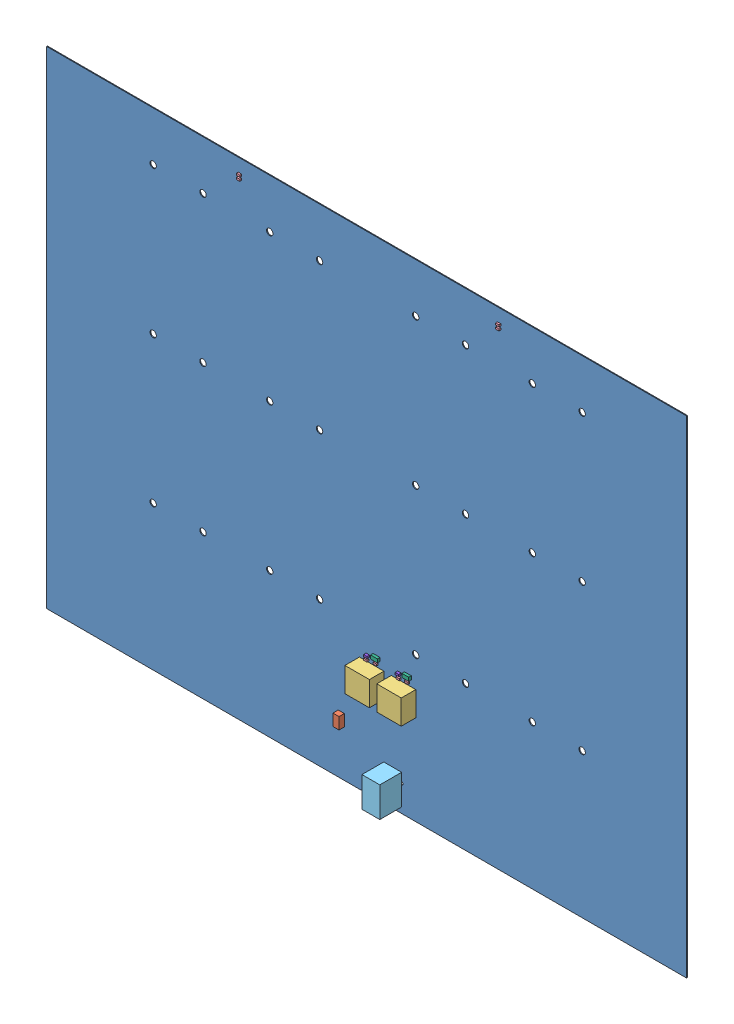
SolidWorks assembly ToasterChargerPcb_November25, configuration Default. Lengths in mm.
Overall size (318.77 242.57 11.41).
55 component instances, 8 part files, 0 mates.
Components (placement in the parent):
- Board-1: Board [Default] at (0 0 -0.4115) size (318.77 242.57 0.41)
- C7_47uF-1: C7_47uF [Default] at origin size (3.05 5.79 2.67)
  - 743509024-1: 743509024 [Default] at (197.7136 76.9366 0.127) size (3.05 5.79 2.67)
    - Extruded-1: Extruded [Default] at origin size (3.05 5.79 2.67)
- U2-1: U2 [Default] at origin size (12.19 12.19 7.24)
  - 580494096-1: 580494096 [Default] at (228.599 101.728 0) size (12.19 12.19 7.24)
    - Extruded_2-1: Extruded_2 [Default] at origin size (12.19 12.19 7.24)
- U1-1: U1 [Default] at origin size (12.19 12.19 7.24)
  - 580494096-1: 580494096 [Default] at (212.724 101.728 0) size (12.19 12.19 7.24)
    - Extruded_2-1: Extruded_2 [Default] at origin size (12.19 12.19 7.24)
- R6-1: R6 [Default] at origin size (1.7 0.95 0.9)
  - 580483600-1: 580483600 [Default] at (230.759 109.347 0) size (1.7 0.95 0.9)
    - Extruded_3-1: Extruded_3 [Default] at origin size (1.7 0.95 0.9)
- R5-1: R5 [Default] at origin size (1.7 0.95 0.9)
  - 580483600-1: 580483600 [Default] at (226.568 108.839 0) size (1.7 0.95 0.9)
    - Extruded_3-1: Extruded_3 [Default] at origin size (1.7 0.95 0.9)
- R3-1: R3 [Default] at origin size (1.7 0.95 0.9)
  - 580483600-1: 580483600 [Default] at (215.138 109.474 0) size (1.7 0.95 0.9)
    - Extruded_3-1: Extruded_3 [Default] at origin size (1.7 0.95 0.9)
- R1-1: R1 [Default] at origin size (1.7 0.95 0.9)
  - 580483600-1: 580483600 [Default] at (210.439 108.839 0) size (1.7 0.95 0.9)
    - Extruded_3-1: Extruded_3 [Default] at origin size (1.7 0.95 0.9)
- P1-1: P1 [Default] at origin size (8.89 14.99 10.87)
  - 743508640-1: 743508640 [Default] at (223.3168 61.2394 0.127) size (8.89 14.99 10.87)
    - Extruded_4-1: Extruded_4 [Default] at origin size (8.89 14.99 10.87)
- C6-1: C6 [Default] at origin size (3.4 1.8 1.3)
  - 580487568-1: 580487568 [Default] at (230.759 111.76 0) size (3.4 1.8 1.3)
    - Extruded_5-1: Extruded_5 [Default] at origin size (3.4 1.8 1.3)
- C5-1: C5 [Default] at origin size (1.45 2.2 1.4)
  - 580501904-1: 580501904 [Default] at (220.726 99.568 0) size (1.45 2.2 1.4)
    - Extruded_6-1: Extruded_6 [Default] at origin size (1.45 2.2 1.4)
- C4-1: C4 [Default] at origin size (1.75 0.95 1.3)
  - 580487056-1: 580487056 [Default] at (226.568 110.871 0) size (1.75 0.95 1.3)
    - Extruded_7-1: Extruded_7 [Default] at origin size (1.75 0.95 1.3)
- C3-1: C3 [Default] at origin size (3.4 1.8 1.3)
  - 580487568-1: 580487568 [Default] at (215.138 111.887 0) size (3.4 1.8 1.3)
    - Extruded_5-1: Extruded_5 [Default] at origin size (3.4 1.8 1.3)
- C2-1: C2 [Default] at origin size (1.45 2.2 1.4)
  - 580501904-1: 580501904 [Default] at (204.978 100.838 0) size (1.45 2.2 1.4)
    - Extruded_6-1: Extruded_6 [Default] at origin size (1.45 2.2 1.4)
- C1-1: C1 [Default] at origin size (1.75 0.95 1.3)
  - 580487056-1: 580487056 [Default] at (210.82 110.744 0) size (1.75 0.95 1.3)
    - Extruded_7-1: Extruded_7 [Default] at origin size (1.75 0.95 1.3)
- R7-1: R7 [Default] at origin size (1.7 0.95 0.9)
  - 580483600-1: 580483600 [Default] at (276.225 284.607 0) size (1.7 0.95 0.9)
    - Extruded_3-1: Extruded_3 [Default] at origin size (1.7 0.95 0.9)
- R2-1: R2 [Default] at origin size (1.7 0.95 0.9)
  - 580483600-1: 580483600 [Default] at (147.078 284.607 0) size (1.7 0.95 0.9)
    - Extruded_3-1: Extruded_3 [Default] at origin size (1.7 0.95 0.9)
- D2-1: D2 [Default] at origin size (1.7 0.95 0.9)
  - 580483600-1: 580483600 [Default] at (276.237 286.385 0) size (1.7 0.95 0.9)
    - Extruded_3-1: Extruded_3 [Default] at origin size (1.7 0.95 0.9)
- D1-1: D1 [Default] at origin size (1.7 0.95 0.9)
  - 580483600-1: 580483600 [Default] at (147.078 286.385 0) size (1.7 0.95 0.9)
    - Extruded_3-1: Extruded_3 [Default] at origin size (1.7 0.95 0.9)
